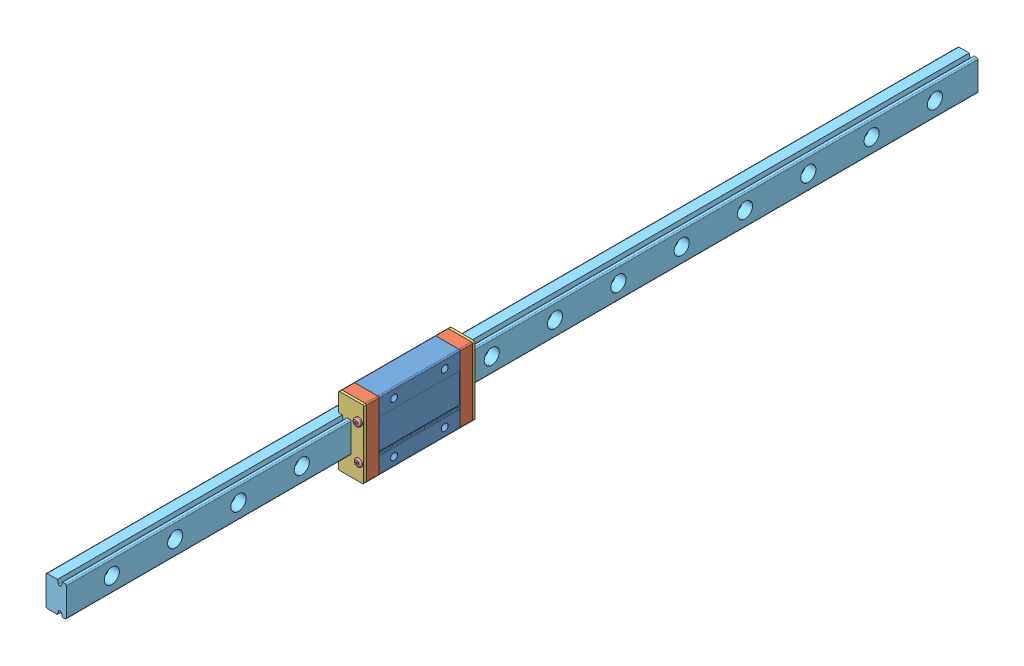
SolidWorks assembly Rail_Assembly360mm, configuration Default. Lengths in mm.
Overall size (13 27 360).
10 component instances, 5 part files, 26 mates.
Components (placement in the parent):
- Main Block-1: Main Block [Default] at (169.1827 226.6144 374.5939) x (0 0 1) z (1 0 0) size (32 27 10)
- Green End Cap-1: Green End Cap [Default] at (174.1827 226.6144 358.5939) x (0 1 0) z (0 0 -1) size (27 10 5)
- Red End Cap-1: Red End Cap [Default] at (174.1827 226.6144 353.5939) x (0 1 0) z (0 0 -1) size (27 10 1)
- Green End Cap-2: Green End Cap [Default] at (174.1827 226.6144 390.5939) x (0 -1 0) z (0 0 1) size (27 10 5)
- Red End Cap-2: Red End Cap [Default] at (174.1827 226.6144 395.5939) x (0 -1 0) z (0 0 1) size (27 10 1)
- Button M3x8-1: Button M3x8 [Default] at (177.1827 219.6144 397.0939) x (0.381849 -0.924225 0) z (0 0 -1) size (3 3 7)
- Button M3x8-2: Button M3x8 [Default] at (177.1827 233.6144 397.5939) x (0.381849 -0.924225 0) z (0 0 -1) size (3 3 7)
- Button M3x8-3: Button M3x8 [Default] at (177.1827 219.6144 352.0939) x (-0.381849 0.924225 0) z (0 0 1) size (3 3 7)
- Button M3x8-5: Button M3x8 [Default] at (177.1827 233.6144 352.0939) x (-0.381849 0.924225 0) z (0 0 1) size (3 3 7)
- Rail 360mm-3: Rail 360mm [Default] at (170.1827 226.6144 554.048) x (0 0 -1) z (1 0 0) size (360 12 8)
Mates (geometry in assembly coordinates):
- Coincident1: coincident: plane of ? through (405.2255 225.8015 379.5515) normal (0 0 1); plane of Main Block-1
- Coincident2: coincident: plane of ? through (405.2255 225.8015 379.5515) normal (0 1 0); plane of Main Block-1
- Coincident3: coincident: plane of Main Block-1 through (179.1827 213.1144 358.5939) normal (0 0 -1); plane of Green End Cap-1 through (174.1827 226.6144 358.5939) normal (0 0 1)
- Coincident4: coincident: plane of Main Block-1 through (179.1827 240.1144 358.5939) normal (0 1 0); plane of Green End Cap-1 through (179.1827 240.1144 353.5939) normal (0 1 0)
- Coincident5: coincident: plane of Main Block-1 through (169.1827 226.6144 374.5939) normal (-1 0 0); plane of Green End Cap-1 through (169.1827 232.6144 353.5939) normal (-1 0 0)
- Coincident9: coincident: plane of Main Block-1 through (179.1827 213.1144 390.5939) normal (0 0 1); plane of Green End Cap-2 through (174.1827 226.6144 390.5939) normal (0 0 -1)
- Coincident10: coincident: plane of Main Block-1 through (179.1827 240.1144 358.5939) normal (0 1 0); plane of Green End Cap-2 through (179.1827 240.1144 395.5939) normal (0 1 0)
- Coincident11: coincident: plane of Main Block-1 through (179.1827 226.6144 374.5939) normal (1 0 0); plane of Green End Cap-2 through (179.1827 240.1144 395.5939) normal (1 0 0)
- Coincident12: coincident: plane of Green End Cap-2 through (174.1827 226.6144 395.5939) normal (0 0 1); plane of Red End Cap-2 through (174.1827 226.6144 395.5939) normal (0 0 -1)
- Coincident13: coincident: plane of Green End Cap-2 through (179.1827 240.1144 395.5939) normal (0 1 0); plane of Red End Cap-2 through (179.1827 240.1144 396.5939) normal (0 1 0)
- Coincident14: coincident: plane of Green End Cap-2 through (179.1827 240.1144 395.5939) normal (1 0 0); plane of Red End Cap-2 through (179.1827 240.1144 396.5939) normal (1 0 0)
- Coincident16: coincident: plane of Green End Cap-1 through (174.1827 226.6144 353.5939) normal (0 0 -1); plane of Red End Cap-1 through (174.1827 226.6144 353.5939) normal (0 0 1)
- Coincident17: coincident: plane of Green End Cap-1 through (179.1827 213.1144 353.5939) normal (0 -1 0); plane of Red End Cap-1 through (179.1827 213.1144 352.5939) normal (0 -1 0)
- Coincident18: coincident: plane of Green End Cap-1 through (169.1827 213.1144 353.5939) normal (-1 0 0); plane of Red End Cap-1 through (169.1827 213.1144 352.5939) normal (-1 0 0)
- Concentric1: concentric: cylinder of Green End Cap-1 through (177.1827 219.6144 358.5939) axis (0 0 -1) radius 1; cylinder of Button M3x8-3 through (177.1827 219.6144 359.0939) axis (0 0 -1) radius 1
- Coincident19: coincident: plane of Red End Cap-1 through (177.1827 219.6144 353.0939) normal (0 0 -1); plane of Button M3x8-3 through (177.1827 219.6144 353.0939) normal (0 0 1)
- Concentric2: concentric: cylinder of Green End Cap-1 through (177.1827 233.6144 358.5939) axis (0 0 -1) radius 1; cylinder of Button M3x8-5 through (177.1827 233.6144 359.0939) axis (0 0 -1) radius 1
- Coincident20: coincident: plane of Red End Cap-1 through (177.1827 233.6144 353.0939) normal (0 0 -1); plane of Button M3x8-5 through (177.1827 233.6144 353.0939) normal (0 0 1)
- Concentric3: concentric: cylinder of Green End Cap-2 through (177.1827 219.6144 390.5939) axis (0 0 1) radius 1; cylinder of Button M3x8-1 through (177.1827 219.6144 390.0939) axis (0 0 1) radius 1
- Coincident21: coincident: plane of Red End Cap-2 through (177.1827 219.6144 396.0939) normal (0 0 1); plane of Button M3x8-1 through (177.1827 219.6144 396.0939) normal (0 0 -1)
- Concentric4: concentric: cylinder of Green End Cap-2 through (177.1827 233.6144 390.5939) axis (0 0 1) radius 1; cylinder of Button M3x8-2 through (177.1827 233.6144 390.5939) axis (0 0 1) radius 1
- Coincident22: coincident: plane of Red End Cap-2 through (174.1827 226.6144 396.5939) normal (0 0 1); plane of Button M3x8-2 through (177.1827 233.6144 396.5939) normal (0 0 -1)
- Coincident24: coincident: plane of Main Block-1; plane of ? through (166.1827 232.5585 379.9218) normal (-1 0 0)
- Coincident25: coincident: plane of Main Block-1; plane of ? through (166.1827 220.5585 379.9218) normal (0 -1 0)
- Coincident27: coincident: plane of Main Block-1 through (174.1827 220.6144 395.5939) normal (-1 0 0); plane of Rail 360mm-3 through (174.1827 232.6144 104.048) normal (1 0 0)
- Coincident28: coincident: plane of Main Block-1 through (172.6827 232.6144 395.5939) normal (0 -1 0); plane of Rail 360mm-3 through (174.1827 232.6144 104.048) normal (0 1 0)
